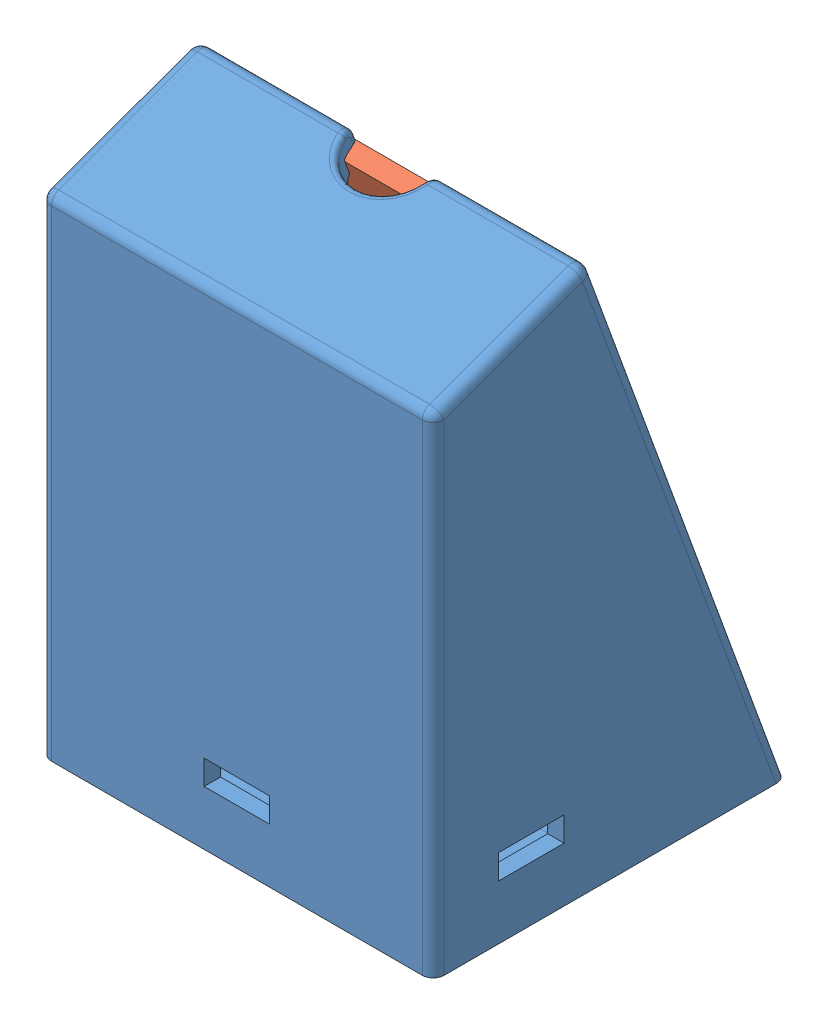
SolidWorks assembly Assembly, configuration Default. Lengths in mm.
Overall size (72 99.44 65).
2 component instances, 2 part files, 3 mates.
Components (placement in the parent):
- project1_t3-1: project1_t3 [Default] at (0 -6.9304 121.4544) size (72 99.44 65)
- Project1_lid (ver.3.0)-1: Project1_lid (ver.3.0) [Default] at (0 42.9286 139.6016) x (1 0 0) z (0 -0.939693 -0.34202) size (65 3.5 100)
Mates (geometry in assembly coordinates):
- Coincident1: coincident anti-aligned: plane of project1_t3-1 through (0 -8.1275 124.7433) normal (0 0.34202 -0.939693); plane of Project1_lid (ver.3.0)-1 through (0 41.7316 142.8905) normal (0 -0.34202 0.939693)
- Coincident3: coincident anti-aligned: plane of project1_t3-1 through (-32.65 -5.2531 125.7895) normal (0 0.939693 0.34202); plane of Project1_lid (ver.3.0)-1 through (-32.5 -5.2531 125.7895) normal (0 -0.939693 -0.34202)
- Distance1: distance = 0.15 mm anti-aligned: plane of Project1_lid (ver.3.0)-1 through (-32.5 -5.2531 125.7895) normal (-1 0 0); plane of project1_t3-1 through (-32.65 -5.2531 125.7895) normal (1 0 0)
